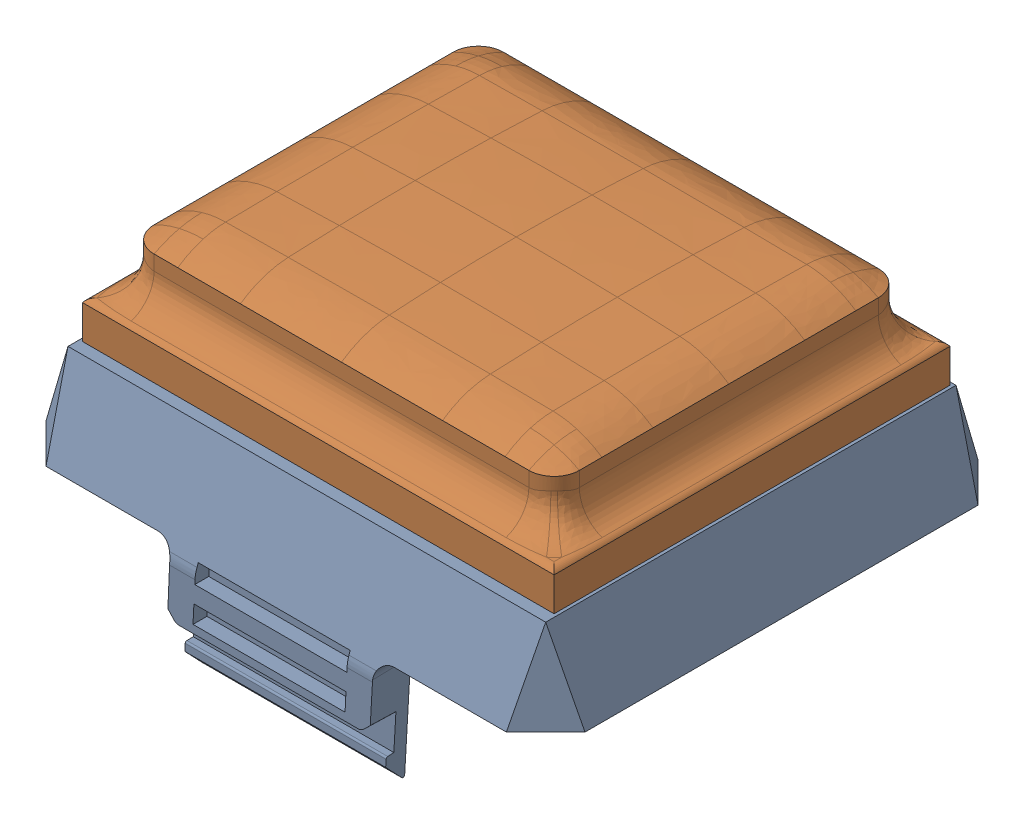
SolidWorks assembly ContiAll, configuration 默认. Lengths in mm.
Overall size (32 17.53 28.9).
7 component instances, 7 part files, 18 mates.
Components (placement in the parent):
- 3Con1612611Support-1: 3Con1612611Support [默认] at origin size (32 12.05 28.9)
- 3Con1612611OriginalSkin_TOP-1: 3Con1612611OriginalSkin_TOP [默认] at (0 2 0) size (28.02 6.25 23.52) (hidden)
- 3Con1612611Lens-1: 3Con1612611Lens [默认] at (-1.1243 18 1.5226) x (1 0 0) z (0 -1 0) size (24.45 17.04 1)
- 3Con1612611UP-2: 3Con1612611UP [默认] at (0 2 0) size (23.8 4.28 19.29)
- 3Con1612lensside-1: 3Con1612lensside [默认] at origin size (28.33 1.42 23.83)
- 3Con1612downskinnew-1: 3Con1612downskinnew [默认] at origin size (23.65 2.2 19.15)
- continuous-1: continuous [默认] at (-9.5635 23.6 -8.5378) x (1 0 0) z (0 -1 0) size (19.5 16.5 0.4)
Mates (geometry in assembly coordinates):
- 重合1: coordinate: point of Support-1
- 重合8: coincident anti-aligned: plane of Support-1 through (-12.1625 18 0) normal (0.996195 0.087156 0); plane of 611Lens-1 through (-12.075 17 -10.5174) normal (-0.996195 -0.087156 0)
- 重合9: coincident anti-aligned: plane of 611OriginalSkin_TOP-1 through (-0.25 24 9.075) normal (0 0 -1); plane of 3Con1612611UP-2 through (-0.25 24 9.075) normal (0 0 1)
- 重合10: coincident anti-aligned: plane of 611OriginalSkin_TOP-1 through (11.575 24 8.375) normal (-1 0 0); plane of 3Con1612611UP-2 through (11.575 24 8.375) normal (1 0 0)
- 重合11: coincident anti-aligned: plane of 611Support-1 through (-13.75 19 11.5) normal (0 -0.34202 -0.939693); plane of lensside-1 through (-13.75 19 11.5) normal (0 0.34202 0.939693)
- 重合12: coincident anti-aligned: plane of 611Support-1 through (-13.75 19 12.7803) normal (0.939693 -0.34202 0); plane of lensside-1 through (-13.75 19 -11.5) normal (-0.939693 0.34202 0)
- 重合14: coincident anti-aligned: plane of 611Lens-1 through (-1.1243 18 1.5226) normal (0 1 0); plane of lensside-1 through (0 18 0) normal (0 -1 0)
- 重合15: coincident anti-aligned: plane of 611Lens-1 through (-1.1243 18 1.5226) normal (0 1 0); plane of downskinnew-1 through (0 18 0) normal (0 -1 0)
- 重合16: coincident anti-aligned: plane of lensside-1 through (-12.075 17.7531 -9.375) normal (1 0 0); plane of downskinnew-1 through (-12.075 17.7531 -9.375) normal (-1 0 0)
- 重合17: coincident anti-aligned: plane of 611OriginalSkin_TOP-1 through (-0.25 24 9.075) normal (0 0 -1); plane of downskinnew-1 through (-11.375 17.7531 9.075) normal (0 0 1)
- 重合18: coincident anti-aligned: plane of lensside-1 through (-11.375 17.7531 9.075) normal (0 0 -1); plane of downskinnew-1 through (-11.375 17.7531 9.075) normal (0 0 1)
- 重合19: coincident anti-aligned: plane of 3Con1612611UP-2 through (-11.375 20.2 -9.375) normal (0 -1 0); plane of downskinnew-1 through (0 20.2 0) normal (0 1 0)
- 重合20: coincident aligned: plane of 3Con1612611UP-2 through (11.575 24 8.375) normal (1 0 0); plane of downskinnew-1 through (11.575 17.7531 -9.375) normal (1 0 0)
- 重合21: coincident anti-aligned: plane of 611OriginalSkin_TOP-1 through (0 19 0) normal (0 -1 0); plane of lensside-1 through (0 19 0) normal (0 1 0)
- 平行1: parallel: plane of 3Con1612611Lens-1 through (-1.1243 17 1.5226) normal (0 -1 0); plane of continuous-1 through (-9.5635 23.2 -30.7243) normal (0 -1 0)
- 平行2: parallel: plane of 3Con1612611UP-2 through (-12.075 24 8.375) normal (-1 0 0); line of continuous-1 through (-11.0635 23.2 -14.2243) axis (0 0 -1)
- 重合23: coincident: line of 3Con1612611UP-2 through (-8.0635 23.6 -4.0378) axis (0 0 1); line of continuous-1 through (-8.0635 23.6 -24.7243) axis (0 0 -1)
- 重合24: coincident anti-aligned: line of 3Con1612611UP-2 through (-8.0635 23.6 6.4622) axis (-1 0 0); line of continuous-1 through (-9.5635 23.6 -15.7243) axis (1 0 0)
